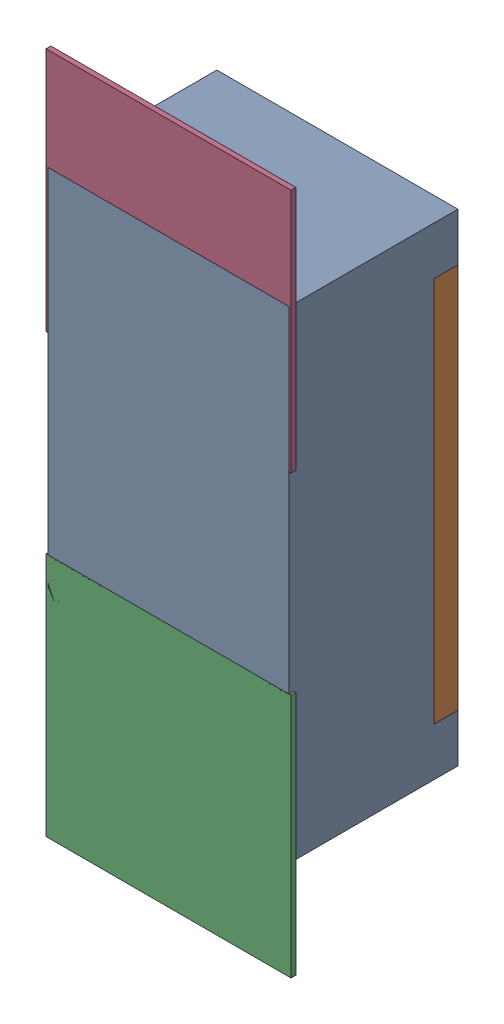
SolidWorks assembly R35, configuration Défaut. Lengths in mm.
Overall size (0.51 1.42 0.35).
5 component instances, 2 part files, 0 mates.
Components (placement in the parent):
- R0402-1: R0402 [Défaut] at (25.0191 -28.321 -2.0818) x (0 -1 0) z (0 0 -1) size (1 0.5 0.35)
- 6504207776-1: 6504207776 [Défaut] at (25.0189 -28.771 -2.0918) size (0.51 0.51 0.01)
  - Extruded-1: Extruded [Défaut] at origin size (0.51 0.51 0.01)
- 6504207776-2: 6504207776 [Défaut] at (25.0189 -27.8639 -2.0918) size (0.51 0.51 0.01)
  - Extruded-1: Extruded [Défaut] at origin size (0.51 0.51 0.01)
